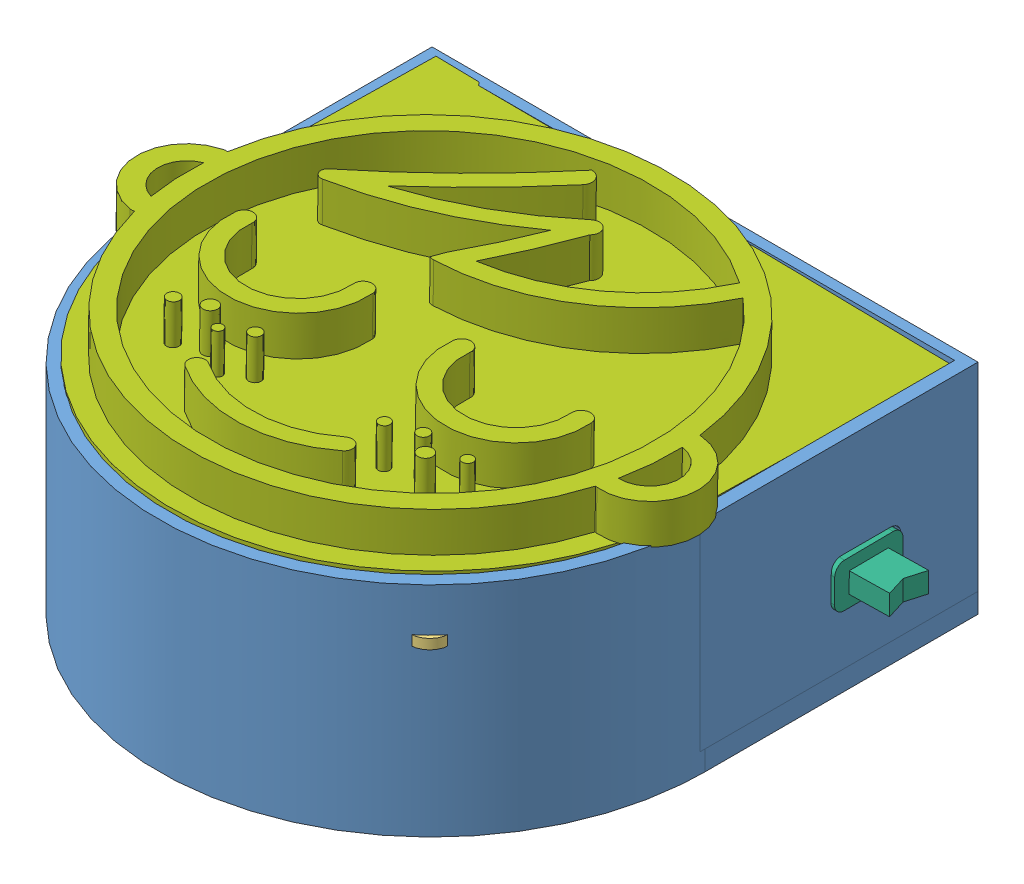
SolidWorks assembly Ensamblaje2 bueno, configuration Predeterminado. Lengths in mm.
Overall size (60.86 26.35 55.05).
7 component instances, 7 part files, 0 mates.
Components (placement in the parent):
- base 2 buena-1: base 2 buena [Predeterminado] at (-3.8432 -10.5773 55.0836) size (55.06 22 55.05)
- bateria lipo-1: bateria lipo [Predeterminado] at (-16.0971 -8.9899 47.4452) x (-0.008727 0 0.999962) z (-0.999962 0 -0.008727) size (35 7 20)
- BT-1: BT [Predeterminado] at (5.6912 6.0335 55.0843) x (-0.008727 0 -0.999962) z (0.999962 0 -0.008727) size (41 4 21)
- cargador-1: cargador [Predeterminado] at (8.8614 -7.6202 46.1492) size (21 5 36)
- placabien-1: placabien [Predeterminado] at (-4.2686 1.6022 56.2745) size (45 4 45)
- switch-1: switch [Predeterminado] at (19.9456 -1.0203 38.9499) x (0.017449 0.008705 0.99981) z (-0.000761 0.999962 -0.008693) size (7 8 4.4)
- cara baby2-1: cara baby2 [Predeterminado] at (-54.5754 11.9557 87.4559) x (0.999911 -0.006671 0.011523) z (-0.011484 0.005819 0.999917) size (57.09 6 52.6)
